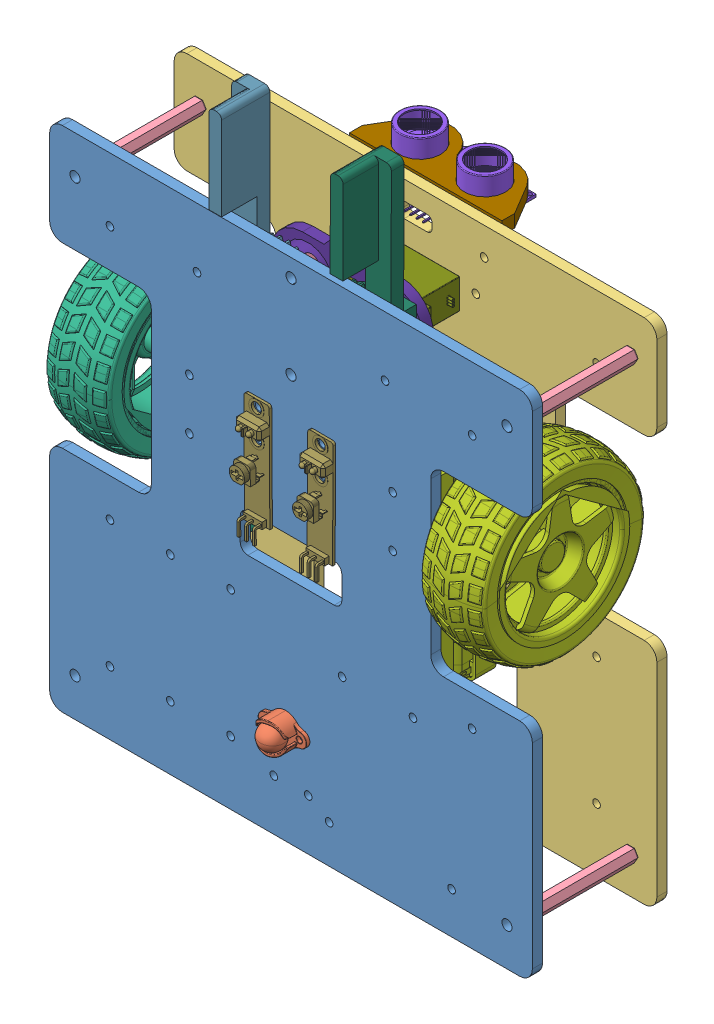
SolidWorks assembly Minibot Assembly, configuration Default. Lengths in mm.
Overall size (190 248.51 90.73).
23 component instances, 17 part files, 35 mates.
Components (placement in the parent):
- Base-1: Base [Default] at (90.6285 215.5162 135.516) size (190 200 4)
- Pololu Ball Caster-1: Pololu Ball Caster [默认] at (90.6285 56.1382 142.3005) x (1 0 0) z (0 -1 0) size (19.05 10.16 12.09)
- Second Layer-1: Second Layer [Default] at (90.6285 215.5162 86.516) size (190 200 4)
- 45 mm standoff male to female-1: 45 mm standoff male to female [默认] at (5.6285 30.5162 135.516) x (1 0 0) z (0 1 0) size (5.77 49.19 5)
- 45 mm standoff male to female-3: 45 mm standoff male to female [默认] at (175.6285 30.5162 135.516) x (1 0 0) z (0 1 0) size (5.77 49.19 5)
- 45 mm standoff male to female-4: 45 mm standoff male to female [默认] at (5.6285 200.5162 135.516) x (1 0 0) z (0 1 0) size (5.77 49.19 5)
- 45 mm standoff male to female-5: 45 mm standoff male to female [默认] at (175.6285 200.5162 135.516) x (1 0 0) z (0 1 0) size (5.77 49.19 5)
- breadboard-1: breadboard [默认] at (89.4751 173.2772 81.266) x (0 1 0) z (-1 0 0) size (56.08 9.51 83.01)
- wheel-motor-right-1: wheel-motor-right [默认] at (7.3771 119.1166 42.4544) x (0 0 -1) z (1 0 0) size (70.1 101.45 57.81)
- wheel-motor-left1-1: wheel-motor-left1 [默认] at (173.88 119.1166 196.0776) x (0 0 1) z (-1 0 0) size (70.1 101.45 57.81)
- US sensor & brackets-1: US sensor & brackets [Default] at (149.321 209.3901 50.9438) size (60 22.1 27.41)
  - Ultrasonic Sensor HC-SR04-1: Ultrasonic Sensor HC-SR04 [默认] at (-74.1795 -19.2479 -12.2709) size (45.2 18.55 25.75)
  - US sensor brackets-1: US sensor brackets [Default] at (-58.6924 7.1261 35.5722) x (-1 0 0) z (0 -1 0) size (60 22.5 15)
- ArduinoUNOR3-3: ArduinoUNOR3 [默认] at (129.4597 52.119 135.516) x (-0.003611 0.999993 0) z (-0.999993 -0.003611 0) size (74.8 15.1 53.3)
- Lipo-1: Lipo [Default] at (5.7825 46.7212 120.516) size (73 30 15)
- IR TCRT5000 sensor-1: IR TCRT5000 sensor [默认] at (103.0817 139.9806 139.516) x (0.006246 0.99998 0) z (0.99998 -0.006246 0) size (46.24 10.91 10)
- IR TCRT5000 sensor-2: IR TCRT5000 sensor [默认] at (78.1754 139.9806 139.516) x (-0.006246 0.99998 0) z (0.99998 0.006246 0) size (46.24 10.91 10)
- Gripper-1: Gripper [Default] at (37.6493 250.3796 172.1854) x (1 0 0) z (0 0 -1) size (80.57 87.5 50.4)
  - Gripper bottom plate-1: Gripper bottom plate [Default] at (52.9792 58.3634 36.6695) size (80.57 41.53 4)
  - gripper-left-2: gripper-left [默认] at (25.2 56.8906 13.8691) x (0 0 -1) z (1 0 0) size (24 80.57 32.03)
  - gripper-right-1: gripper-right [默认] at (69.7562 70.798 72.4698) x (0 0 1) z (0.003687 -0.999993 0) size (24 31.9 82.67)
  - SG90-1: SG90 [默认] at (75.0792 64.2634 77.0695) x (0 -1 0) z (1 0 0) size (11.82 29.9 31.9)
  - Gripper top plate-1: Gripper top plate [Default] at (52.9792 58.3634 58.6695) x (1 0 0) z (0 0 -1) size (60 41.53 11)
Mates (geometry in assembly coordinates):
- Coincident1: coincident: plane of Base-1 through (90.6285 215.5162 135.516) normal (1 0 0); plane of Pololu Ball Caster-1 through (90.6285 56.1382 142.3005) normal (1 0 0)
- Parallel1: parallel: plane of Base-1 through (0.6285 20.5162 135.516) normal (0 0 -1); plane of Pololu Ball Caster-1 through (83.3299 59.9626 141.606) normal (0 0 -1)
- Coincident4: coincident: plane of Base-1 through (0.6285 215.5162 139.516) normal (0 1 0); plane of Second Layer-1 through (0.6285 215.5162 90.516) normal (0 1 0)
- Coincident5: coincident: plane of Base-1 through (0.6285 20.5162 135.516) normal (0 0 -1); plane of 45 mm standoff male to female-1 through (5.6285 30.5162 135.516) normal (0 0 1)
- Concentric1: concentric: cylinder of Base-1 through (5.6285 30.5162 119.516) axis (0 0 1) radius 2; circle of 45 mm standoff male to female-1
- Coincident7: coincident: plane of Base-1 through (0.6285 20.5162 135.516) normal (0 0 -1); plane of 45 mm standoff male to female-3 through (175.6285 30.5162 135.516) normal (0 0 1)
- Concentric2: concentric: cylinder of Base-1 through (175.6285 30.5162 119.516) axis (0 0 1) radius 2; circle of 45 mm standoff male to female-3
- Coincident8: coincident: plane of Base-1 through (0.6285 20.5162 135.516) normal (0 0 -1); plane of 45 mm standoff male to female-4 through (5.6285 200.5162 135.516) normal (0 0 1)
- Concentric3: concentric: circle of Base-1; circle of 45 mm standoff male to female-4
- Coincident9: coincident: plane of Base-1 through (0.6285 20.5162 135.516) normal (0 0 -1); plane of 45 mm standoff male to female-5 through (175.6285 200.5162 135.516) normal (0 0 1)
- Concentric4: concentric: cylinder of Base-1 through (175.6285 200.5162 119.516) axis (0 0 1) radius 2; circle of 45 mm standoff male to female-5
- Distance1: distance = 45 mm: plane of Base-1 through (0.6285 20.5162 135.516) normal (0 0 -1); plane of Second Layer-1 through (180.6285 20.5162 90.516) normal (0 0 1)
- Coincident11: coincident: plane of Base-1 through (185.6285 210.5162 139.516) normal (1 0 0); plane of Second Layer-1 through (185.6285 210.5162 90.516) normal (1 0 0)
- Coincident12: coincident: plane of Second Layer-1 through (180.6285 20.5162 86.516) normal (0 0 -1); plane of breadboard-1 through (131.3851 131.3672 86.516) normal (0 0 1)
- Coincident23: coincident: plane of Base-1 through (0.6285 20.5162 135.516) normal (0 0 -1); plane of wheel-motor-right-1 through (45.0285 116.6072 135.516) normal (0 0 1)
- Coincident25: coincident: plane of Base-1 through (0.6285 20.5162 135.516) normal (0 0 -1); plane of wheel-motor-left1-1 through (136.2285 116.6072 135.516) normal (0 0 1)
- Coincident26: coincident: plane of wheel-motor-right-1 through (54.4285 166.6072 135.516) normal (0 1 0); plane of wheel-motor-left1-1 through (126.8285 166.6072 135.516) normal (0 1 0)
- Distance3: distance = 2.09 mm: plane of Base-1 through (0.6285 20.5162 139.516) normal (0 0 1); plane of Pololu Ball Caster-1 through (83.3299 59.9626 141.606) normal (0 0 -1)
- Coincident28: coincident: plane of Base-1 through (90.6285 215.5162 135.516) normal (1 0 0); plane of US sensor & brackets-1/US sensor brackets-1 through (90.6285 216.5162 86.516) normal (-1 0 0)
- Coincident29: coincident: plane of Second Layer-1 through (180.6285 20.5162 86.516) normal (0 0 -1); plane of US sensor & brackets-1/US sensor brackets-1 through (60.6285 211.5162 86.516) normal (0 0 1)
- Coincident32: coincident: plane of Base-1 through (35.6285 170.5162 139.516) normal (-1 0 0); plane of wheel-motor-right-1 through (35.6285 137.5322 119.266) normal (-1 0 0)
- Coincident36: coincident: plane of Base-1 through (145.6285 167.5764 139.516) normal (1 0 0); plane of wheel-motor-left1-1 through (145.6285 137.5322 119.266) normal (1 0 0)
- Coincident37: coincident: plane of Base-1 through (0.6285 20.5162 135.516) normal (0 0 -1); plane of ArduinoUNOR3-3 through (129.4597 52.119 135.516) normal (0 0 1)
- Concentric5: concentric: cylinder of Base-1 through (153.8285 31.8162 135.516) axis (0 0 1) radius 1.5; cylinder of ArduinoUNOR3-3 through (153.8285 31.8162 133.916) axis (0 0 1) radius 1.6
- Coincident40: coincident: plane of Base-1 through (0.6285 20.5162 139.516) normal (0 0 1); plane of IR TCRT5000 sensor-1 through (103.0817 139.9806 139.516) normal (0 0 -1)
- Concentric9: concentric: cylinder of Base-1 through (103.1972 158.4802 145.516) axis (0 0 -1) radius 1.5; cylinder of IR TCRT5000 sensor-1 through (103.1972 158.4802 140.516) axis (0 0 -1) radius 2
- Concentric10: concentric: cylinder of Base-1 through (103.1285 147.4804 145.516) axis (0 0 -1) radius 1.5; cylinder of IR TCRT5000 sensor-1 through (103.1285 147.4804 140.516) axis (0 0 -1) radius 2
- Coincident41: coincident: plane of Base-1 through (0.6285 20.5162 139.516) normal (0 0 1); plane of IR TCRT5000 sensor-2 through (78.1754 139.9806 139.516) normal (0 0 -1)
- Concentric11: concentric: cylinder of Base-1 through (78.0598 158.4802 145.516) axis (0 0 -1) radius 1.5; cylinder of IR TCRT5000 sensor-2 through (78.0598 158.4802 140.516) axis (0 0 -1) radius 2
- Concentric12: concentric: cylinder of Base-1 through (78.1285 147.4804 145.516) axis (0 0 -1) radius 1.5; cylinder of IR TCRT5000 sensor-2 through (78.1285 147.4804 140.516) axis (0 0 -1) radius 2
- Coincident42: coincident: plane of Base-1 through (0.6285 20.5162 135.516) normal (0 0 -1); plane of Gripper-1/Gripper bottom plate-1 through (53.6285 192.0162 135.516) normal (0 0 1)
- Concentric13: concentric: cylinder of Base-1 through (127.6285 192.0162 135.516) axis (0 0 1) radius 1.5; cylinder of Gripper-1/Gripper bottom plate-1 through (127.6285 192.0162 131.516) axis (0 0 1) radius 1.5
- Concentric14: concentric: cylinder of Base-1 through (53.6285 192.0162 135.516) axis (0 0 1) radius 1.5; cylinder of Gripper-1/Gripper bottom plate-1 through (53.6285 192.0162 131.516) axis (0 0 1) radius 1.5
- Coincident43: coincident: plane of Base-1 through (0.6285 20.5162 135.516) normal (0 0 -1); plane of Lipo-1 through (5.7825 46.7212 135.516) normal (0 0 1)
- Concentric15: concentric: cylinder of Second Layer-1 through (63.6285 204.5162 80.516) axis (0 0 1) radius 1.5; cylinder of US sensor & brackets-1/US sensor brackets-1 through (63.6285 204.5162 93.516) axis (0 0 -1) radius 1.5
